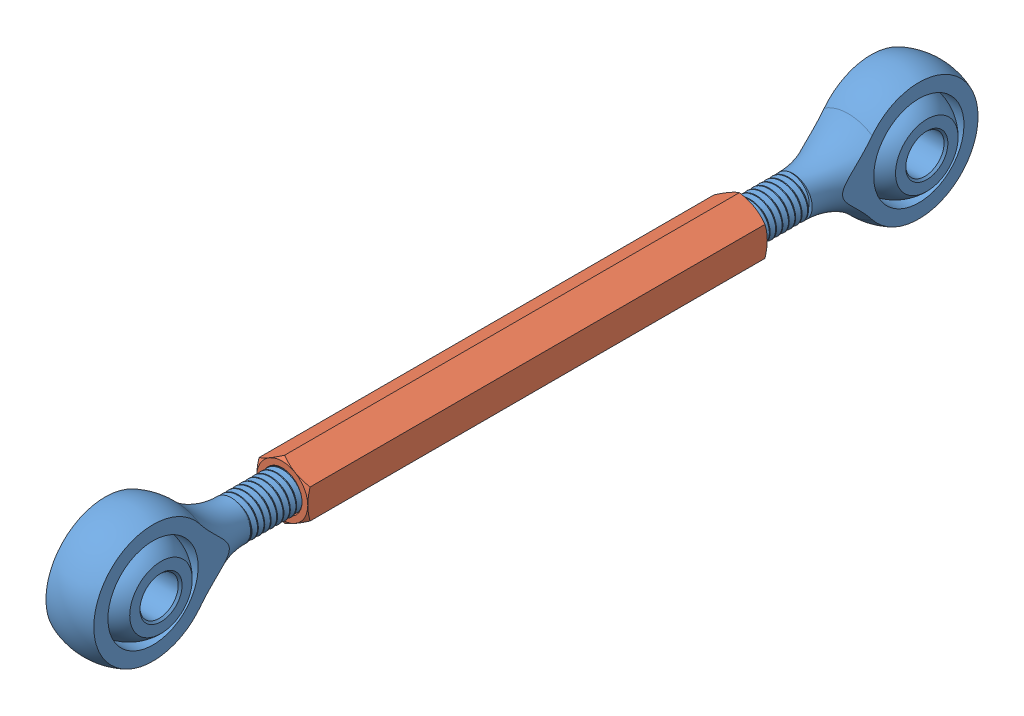
SolidWorks assembly Inboard Autothrottle Linkage Rod, configuration Default. Lengths in mm.
Overall size (7.94 15.88 111.12).
3 component instances, 2 part files, 5 mates.
Components (placement in the parent):
- 60645K111_STEEL BALL JOINT ROD END RH-1: 60645K111_STEEL BALL JOINT ROD END RH [60645K111] at (13.5009 -18.9454 -71.8464) x (0 1 0) z (-1 0 0) size (15.88 39.82 7.94)
- 60645K111_STEEL BALL JOINT ROD END RH-2: 60645K111_STEEL BALL JOINT ROD END RH [60645K111] at (13.5009 -18.9454 -1.9964) x (0 1 0) z (1 0 0) size (15.88 39.82 7.94)
- 91780A044 - STANDOFF, HEX, FEMALE, 10-32 X 2.25 L X .25 HEX, ALUMINUM-1: 91780A044 - STANDOFF, HEX, FEMALE, 10-32 X 2.25 L X .25 HEX, ALUMINUM [91780A044] at (13.5009 -18.9454 -36.9214) size (6.35 7.33 57.77)
Mates (geometry in assembly coordinates):
- Distance32: distance = 31.75 mm anti-aligned: plane of 60645K111_STEEL BALL JOINT ROD END RH-2 through (13.5009 -18.9454 -21.0464) normal (0 0 -1); plane of 60645K111_STEEL BALL JOINT ROD END RH-1 through (13.5009 -18.9454 -52.7964) normal (0 0 1)
- Concentric163: concentric anti-aligned: circle of 60645K111_STEEL BALL JOINT ROD END RH-1; circle of 60645K111_STEEL BALL JOINT ROD END RH-2
- Coincident2: coincident: plane of 60645K111_STEEL BALL JOINT ROD END RH-1 through (13.5009 -18.9454 -71.8464) normal (-1 0 0); plane of 91780A044 - STANDOFF, HEX, FEMALE, 10-32 X 2.25 L X .25 HEX, ALUMINUM-1 through (13.5009 -18.9454 -36.9214) normal (1 0 0)
- Width1: width: plane of 91780A044 - STANDOFF, HEX, FEMALE, 10-32 X 2.25 L X .25 HEX, ALUMINUM-1 through (13.5009 -15.2792 -65.4964) normal (0 0 -1); plane of 60645K111_STEEL BALL JOINT ROD END RH-2 through (13.5009 -15.2792 -8.3464) normal (0 0 1); plane of 91780A044 - STANDOFF, HEX, FEMALE, 10-32 X 2.25 L X .25 HEX, ALUMINUM-1 through (13.5009 -18.9454 -21.0464) normal (0 0 -1); plane of 60645K111_STEEL BALL JOINT ROD END RH-1 through (13.5009 -18.9454 -52.7964) normal (0 0 1)
- Concentric164: concentric aligned: circle of 60645K111_STEEL BALL JOINT ROD END RH-2; circle of 91780A044 - STANDOFF, HEX, FEMALE, 10-32 X 2.25 L X .25 HEX, ALUMINUM-1
